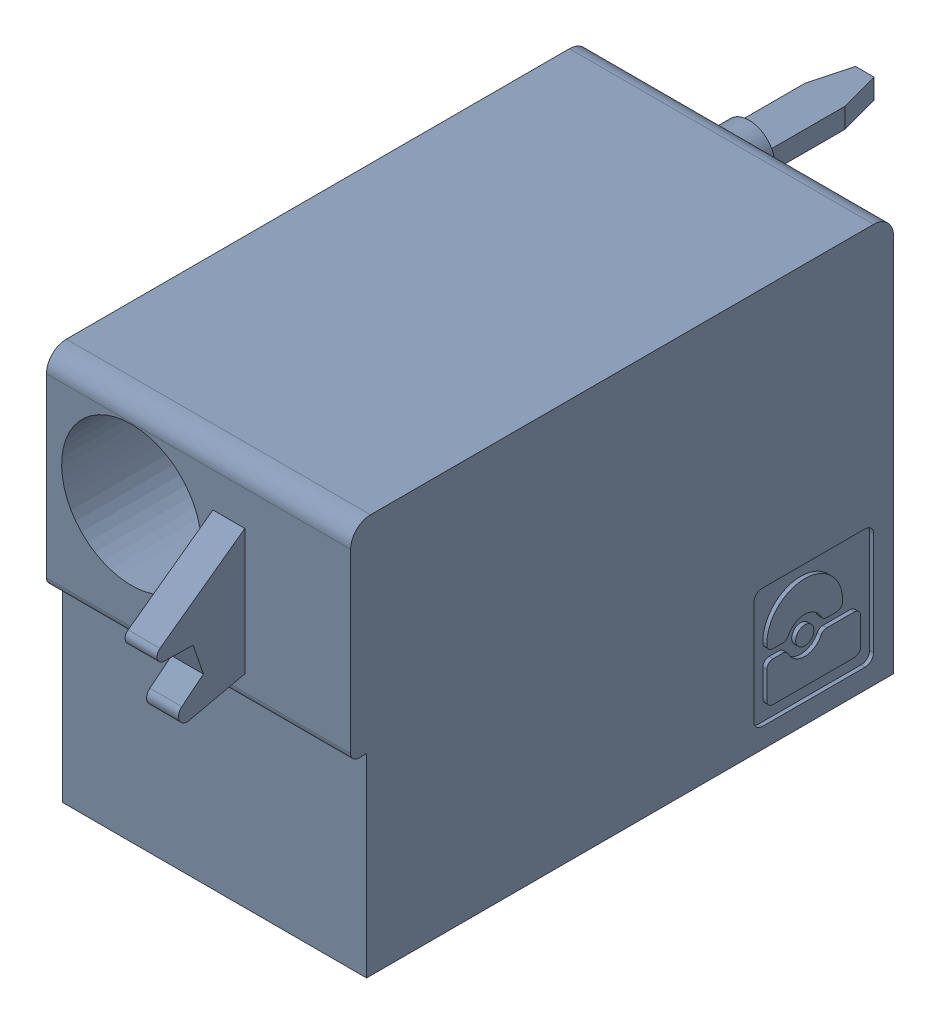
SolidWorks assembly J62, configuration Default. Lengths in mm.
Overall size (7.62 10 19.2).
2 component instances, 1 part files, 0 mates.
Components (placement in the parent):
- 1790487-1: 1790487 [Default] at (170.585 -5.67 -10.6) x (0 1 0) z (1 0 0) size (10 19.2 7.62)
  - ffkdsa1-v2-7.62-1: ffkdsa1-v2-7.62 [Default] at (-15.6914 -27.508 9.12) x (0 -1 0) z (0 0 1) size (19.2 10 7.62)
